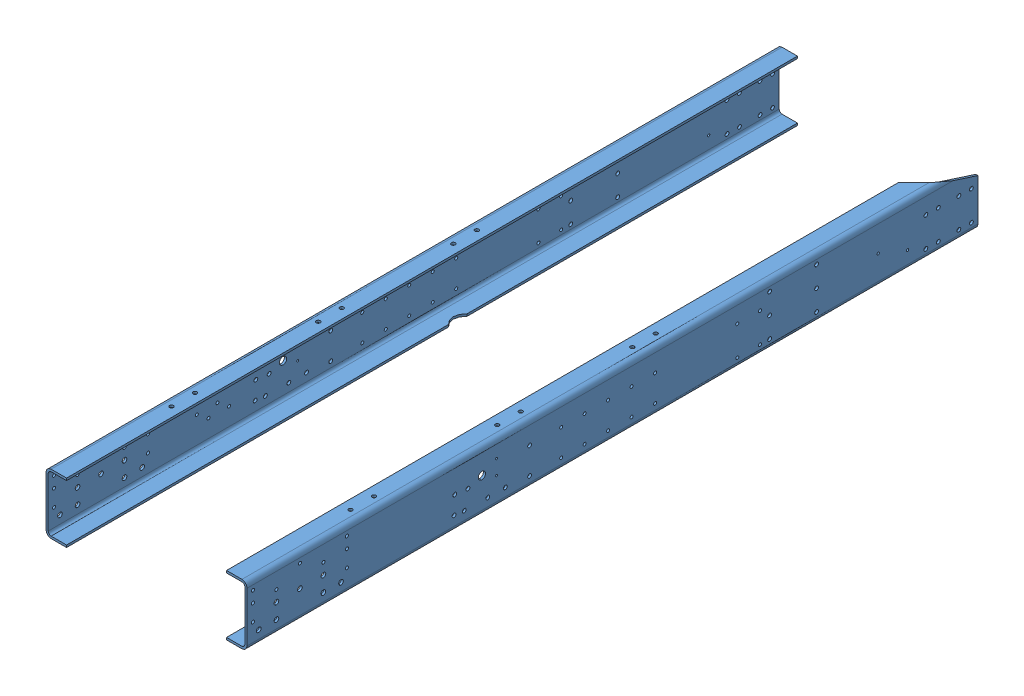
SolidWorks assembly 3994-CC1, configuration Both Rails. Lengths in mm.
Overall size (869.95 260.35 3162.3).
2 component instances, 1 part files, 6 mates.
Components (placement in the parent):
- 1982-CC1-1: 1982-CC1 [1982-CC1-124.50] at (434.975 0 1333.5) size (88.9 260.35 3162.3)
- 1982-CC1-2: 1982-CC1 [1982-CC1-124.50] at (-434.975 0 -1828.8) x (-1 0 0) z (0 0 -1) size (88.9 260.35 3162.3)
Mates (geometry in assembly coordinates):
- Coincident1: coincident aligned: plane of ?; plane of assembly
- Coincident2: coincident aligned: plane of ?; plane of assembly
- Coincident3: coincident aligned: plane of ?; plane of assembly
- Coincident4: coincident anti-aligned: plane of ?; plane of assembly
- Coincident5: coincident anti-aligned: plane of ?; plane of assembly
- Coincident6: coincident aligned: 
